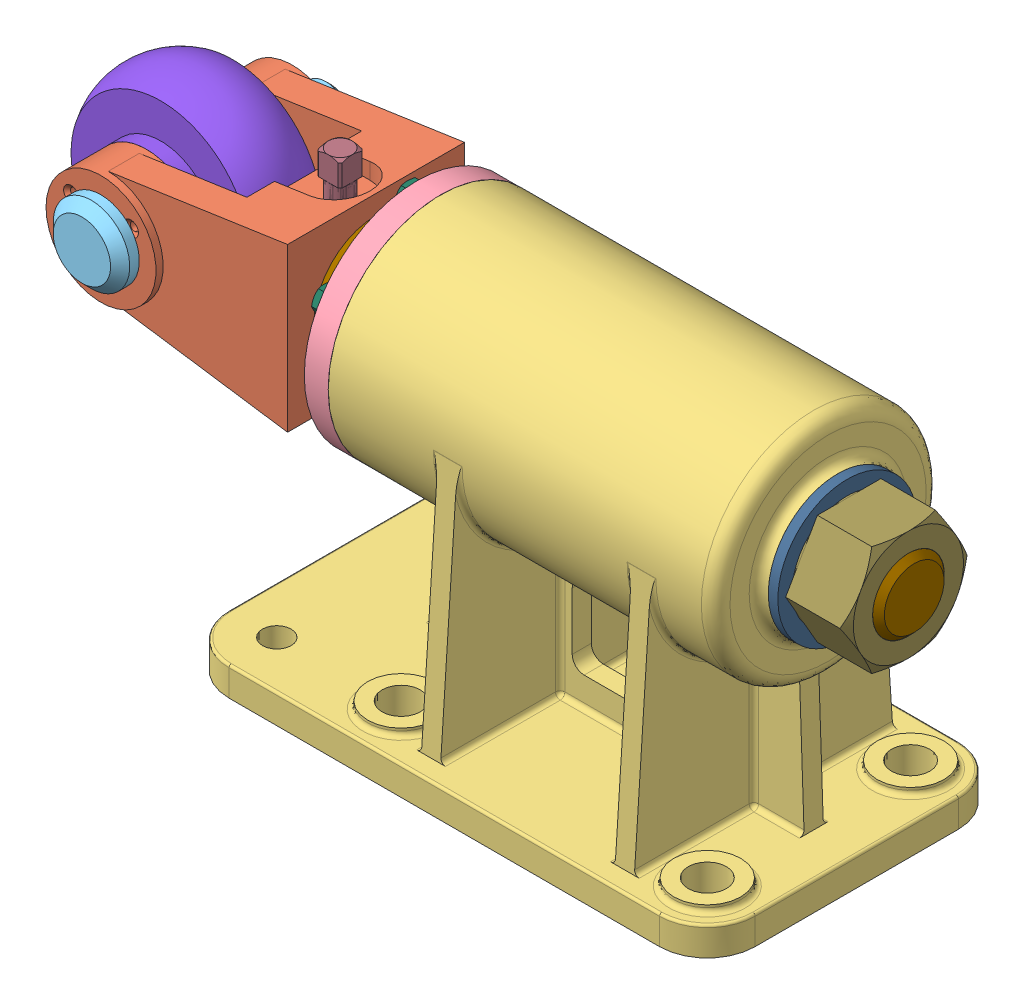
SolidWorks assembly Сборка, configuration Default. Lengths in mm.
Overall size (343.16 167.36 125).
22 component instances, 16 part files, 54 mates.
Components (placement in the parent):
- Втулка-1: Втулка [Default] at (796.4471 -433.9108 62.5) x (-1 0 0) z (0 -0.999974 0.007231) size (35 68 68)
- Вилка-1: Вилка [Default] at (641.6216 -433.9108 32) x (0 1 0) z (1 0 0) size (68 80 98)
- Корпус-1: Корпус [Default] at (807.6216 -550.9108 62.5) size (220 164 125)
- Крышка-1: Крышка [Default] at (727.6216 -433.9108 62.5) size (46 94 94)
- Ось-1: Ось [Default] at (641.6216 -423.9108 102.5) x (0 0 -1) z (0 1 0) size (104 32 32)
- Планка-1: Планка [Default] at (641.6216 -423.9108 19.5) x (1 0 0) z (0 -1 0) size (34 3 8)
- Пружина-1: Пружина [Default] at (888.6216 -433.9108 62.5) x (-1 0 0) z (0 -0.527884 -0.849317) size (97.96 73.13 73.13)
- Ролик-1: Ролик [Default] at (641.6216 -433.9108 62.5) x (0 0 -1) z (-0.999609 -0.027945 0) size (42 84 84)
- Стержень-1: Стержень [Default] at (686.6216 -433.9108 62.5) x (1 0 0) z (0 1 0) size (255 52 52)
- Шайба-1: Шайба [Default] at (913.6216 -433.9108 62.5) x (1 0 0) z (0 0.218534 -0.975829) size (4 58 58)
- parallel_din-1: parallel_din [Parallel key A12 x 8 x 32 DIN 6885] at (739.6216 -450.1144 62.5) x (-1 0 0) z (0 0 1) size (32 8 12)
- hex nut style 1 gradeab_iso-3: hex nut style 1 gradeab_iso [ISO - 4032 - M30 - W - N] at (939.2216 -433.9108 62.5) x (0 0.5 -0.866025) z (1 0 0) size (46 53.12 25.6)
- square head bolt dog pt_din-3: square head bolt dog pt_din [DIN 479 - M10 x 16-C] at (701.6216 -390.9108 62.5) x (0 -1 0) z (-0.707107 0 0.707107) size (26 13 13)
- slotted set screw flat point_iso-3: slotted set screw flat point_iso [ISO 4766 - M6 x 12-N] at (641.915 -444.4067 41.5) x (0 0 1) z (0 1 0) size (12 6 6)
- hex bolt gradeab_iso-4: hex bolt gradeab_iso [ISO 4014 - M6 x 30 x 18-N] at (729.6216 -393.9108 62.5) x (1 0 0) z (0 0.5 0.866025) size (34 11.55 10)
- hex bolt gradeab_iso-6: hex bolt gradeab_iso [ISO 4014 - M6 x 30 x 18-N] at (729.6216 -413.9108 27.859) x (1 0 0) z (0 1 0) size (34 11.55 10)
- hex bolt gradeab_iso-7: hex bolt gradeab_iso [ISO 4014 - M6 x 30 x 18-N] at (729.6216 -453.9108 27.859) x (1 0 0) z (0 0.5 -0.866025) size (34 11.55 10)
- hex bolt gradeab_iso-8: hex bolt gradeab_iso [ISO 4014 - M6 x 30 x 18-N] at (729.6216 -473.9108 62.5) x (1 0 0) z (0 -0.5 -0.866025) size (34 11.55 10)
- hex bolt gradeab_iso-9: hex bolt gradeab_iso [ISO 4014 - M6 x 30 x 18-N] at (729.6216 -453.9108 97.141) x (1 0 0) z (0 -1 0) size (34 11.55 10)
- hex bolt gradeab_iso-10: hex bolt gradeab_iso [ISO 4014 - M6 x 30 x 18-N] at (729.6216 -413.9108 97.141) x (1 0 0) z (0 -0.5 0.866025) size (34 11.55 10)
- pan head cross recess screw_iso-1: pan head cross recess screw_iso [ISO 7045 - M4 x 16 - Z - 16N] at (654.1216 -423.9108 16.4) x (0 0 1) z (-0.923728 -0.383049 0) size (19.02 8 8)
- pan head cross recess screw_iso-3: pan head cross recess screw_iso [ISO 7045 - M4 x 16 - Z - 16N] at (629.1216 -423.9108 16.4) x (0 0 1) z (-0.923728 0.383049 0) size (19.02 8 8)
Mates (geometry in assembly coordinates):
- Parallel2: parallel aligned: plane of Корпус-1 through (897.6216 -538.9108 20) normal (0 1 0); plane of Крышка-1 through (773.6216 -458.1144 56.5) normal (0 1 0)
- Concentric5: concentric aligned: circle of Крышка-1; circle of Стержень-1
- Parallel4: parallel anti-aligned: plane of Крышка-1 through (773.6216 -458.1144 56.5) normal (0 1 0); plane of Стержень-1 through (759.6216 -449.9108 62.5) normal (0 -1 0)
- Coincident11: coincident anti-aligned: plane of Втулка-1 through (798.6216 -457.9102 62.6735) normal (1 0 0); plane of Пружина-1 through (798.6216 -433.9108 62.5) normal (-1 0 0)
- Coincident12: coincident anti-aligned: plane of Втулка-1 through (791.6216 -467.9099 62.7458) normal (-1 0 0); plane of Стержень-1 through (791.6216 -413.9108 62.5) normal (1 0 0)
- Concentric7: concentric anti-aligned: cylinder of Стержень-1 through (598.8447 -433.9108 62.5) axis (-1 0 0) radius 15; cylinder of hex nut style 1 gradeab_iso-3 through (913.6216 -433.9108 62.5) axis (1 0 0) radius 13.25
- Coincident13: coincident anti-aligned: plane of Шайба-1 through (913.6216 -429.9772 44.9351) normal (1 0 0); plane of hex nut style 1 gradeab_iso-3 through (913.6216 -410.9108 75.7791) normal (-1 0 0)
- Parallel5: parallel aligned: plane of Корпус-1 through (897.6216 -538.9108 20) normal (0 1 0); plane of hex nut style 1 gradeab_iso-3 through (913.6216 -410.9108 49.2209) normal (0 1 0)
- Concentric8: concentric anti-aligned: cylinder of Вилка-1 through (618.6216 -433.9108 62.5) axis (1 0 0) radius 20; cylinder of Стержень-1 through (598.8447 -433.9108 62.5) axis (-1 0 0) radius 20
- Coincident15: coincident anti-aligned: plane of Вилка-1 through (716.6216 -433.9108 38.5) normal (1 0 0); plane of Стержень-1 through (716.6216 -413.9108 62.5) normal (-1 0 0)
- Coincident16: coincident anti-aligned: line of Втулка-1 through (791.6216 -433.9108 62.5) axis (1 0 0); line of Пружина-1 through (888.6216 -433.9108 62.5) axis (-1 0 0)
- Lock3: lock: unknown of Втулка-1; unknown of Стержень-1
- Parallel6: parallel: line of Вилка-1 through (716.6216 -467.9108 99.5) axis (0 0 -1); plane of Корпус-1 through (897.6216 -538.9108 20) normal (0 1 0)
- Coincident17: coincident aligned: circle of Вилка-1; cylinder of Ось-1 through (641.6216 -433.9108 34.6227) axis (0 0 -1) radius 10
- Concentric9: concentric anti-aligned: cylinder of Вилка-1 through (629.1216 -423.9108 22.5) axis (0 0 -1) radius 1.7; circle of Планка-1
- Concentric11: concentric anti-aligned: circle of Вилка-1; circle of Планка-1
- Parallel9: parallel anti-aligned: plane of Ось-1 through (409.8471 -427.9108 22.5) normal (0 1 0); plane of Планка-1 through (624.6216 -427.9108 22.5) normal (0 -1 0)
- Coincident22: coincident anti-aligned: plane of Ось-1 through (409.8471 -427.9108 19.5) normal (0 0 1); plane of Планка-1 through (641.6216 -423.9108 19.5) normal (0 0 -1)
- Coincident23: coincident anti-aligned: plane of Вилка-1 through (641.6216 -433.9108 22.5) normal (0 0 -1); plane of Планка-1 through (641.6216 -423.9108 22.5) normal (0 0 1)
- Coincident27: coincident anti-aligned: plane of Стержень-1 through (759.6216 -449.9108 56.5) normal (0 0 1); plane of parallel_din-1 through (759.6216 -458.1144 56.5) normal (0 0 -1)
- Concentric16: concentric anti-aligned: cylinder of Стержень-1 through (739.6216 -449.9108 62.5) axis (0 -1 0) radius 6; cylinder of parallel_din-1 through (739.6216 -458.1144 62.5) axis (0 1 0) radius 6
- Coincident41: coincident anti-aligned: line of Пружина-1 through (888.6216 -433.9108 62.5) axis (-1 0 0); axis of hex nut style 1 gradeab_iso-3 through (914.8724 -433.9108 62.5) axis (1 0 0)
- Coincident42: coincident anti-aligned: line of Корпус-1 through (1195.0065 -433.9108 62.5) axis (-1 0 0); line of hex nut style 1 gradeab_iso-3 through (914.8724 -433.9108 62.5) axis (1 0 0)
- Coincident43: coincident aligned: circle of Корпус-1; circle of Шайба-1
- Coincident44: coincident anti-aligned: plane of Корпус-1 through (888.6216 -466.9108 62.5) normal (-1 0 0); plane of Пружина-1 through (888.6216 -433.9108 62.5) normal (1 0 0)
- Coincident45: coincident anti-aligned: plane of Корпус-1 through (743.6216 -480.9108 62.5) normal (-1 0 0); plane of Крышка-1 through (743.6216 -433.9108 29.5) normal (1 0 0)
- Coincident46: coincident aligned: circle of Корпус-1; circle of Крышка-1
- Parallel16: parallel aligned: plane of Корпус-1 through (897.6216 -538.9108 20) normal (0 1 0); plane of hex nut style 1 gradeab_iso-3 through (913.6216 -410.9108 49.2209) normal (0 1 0)
- Parallel17: parallel anti-aligned: plane of parallel_din-1 through (759.6216 -458.1144 62.5) normal (0 -1 0); plane of Корпус-1 through (897.6216 -538.9108 20) normal (0 1 0)
- Lock7: lock: unknown of Пружина-1; unknown of Стержень-1
- Lock8: lock: unknown of Шайба-1; unknown of hex nut style 1 gradeab_iso-3
- Coincident50: coincident anti-aligned: plane of Крышка-1 through (773.6216 -458.1144 56.5) normal (0 1 0); plane of parallel_din-1 through (759.6216 -458.1144 62.5) normal (0 -1 0)
- Concentric18: concentric aligned: cylinder of Вилка-1 through (701.6216 -467.9118 62.5) axis (0 1 0) radius 5; cylinder of square head bolt dog pt_din-3 through (701.6216 -390.9108 62.5) axis (0 1 0) radius 5
- Parallel19: parallel aligned: plane of Вилка-1 through (686.6216 -463.5108 62.5) normal (-1 0 0); plane of square head bolt dog pt_din-3 through (696.6216 -400.9108 58.3467) normal (-1 0 0)
- Parallel20: parallel anti-aligned: plane of Вилка-1 through (701.6216 -408.9108 62.5) normal (0 1 0); plane of square head bolt dog pt_din-3 through (701.6216 -400.9108 62.5) normal (0 -1 0)
- Concentric19: concentric aligned: line of Корпус-1 through (1195.0065 -433.9108 62.5) axis (-1 0 0); cylinder of slotted set screw flat point_iso-2 through (1050.1594 -433.7358 242.2554) axis (-0.999907 -0.000033 -0.013618) radius 3
- Concentric20: concentric aligned: cylinder of Ролик-1 through (641.915 -444.4067 41.5) axis (0 0 -1) radius 3.3; cylinder of slotted set screw flat point_iso-3 through (641.915 -444.4067 28.8) axis (0 0 -1) radius 3
- Coincident55: coincident: point of Стержень-1; plane of square head bolt dog pt_din-3 through (701.6216 -416.9108 62.5) normal (0 -1 0)
- Parallel21: parallel: plane of Вилка-1 through (686.6216 -463.5108 62.5) normal (-1 0 0); line of slotted set screw flat point_iso-3 through (641.415 -442.0129 41.5) axis (0 -1 0)
- Concentric21: concentric aligned: cylinder of Крышка-1 through (773.6216 -393.9108 62.5) axis (-1 0 0) radius 3.3; cylinder of hex bolt gradeab_iso-4 through (729.6216 -393.9108 62.5) axis (-1 0 0) radius 3
- Coincident57: coincident anti-aligned: plane of Крышка-1 through (733.6216 -433.9108 15.5) normal (-1 0 0); plane of hex bolt gradeab_iso-4 through (733.6216 -388.9108 59.6132) normal (1 0 0)
- Parallel22: parallel aligned: plane of Корпус-1 through (897.6216 -538.9108 20) normal (0 1 0); plane of hex bolt gradeab_iso-4 through (733.6216 -388.9108 59.6132) normal (0 1 0)
- Concentric22: concentric aligned: cylinder of Планка-1 through (654.1216 -423.9108 22.5) axis (0 0 -1) radius 2; cylinder of hex bolt gradeab_iso-12 through (654.1216 -423.9108 16.7) axis (0 0 -1) radius 2
- Coincident59: coincident anti-aligned: plane of Планка-1 through (641.6216 -423.9108 19.5) normal (0 0 -1); circle of hex bolt gradeab_iso-12
- Parallel23: parallel aligned: plane of Вилка-1 through (638.3193 -411.3952 38.5) normal (-0.145114 0.989415 0); plane of hex bolt gradeab_iso-12 through (651.6144 -420.7411 19.5) normal (-0.145114 0.989415 0)
- Coincident60: coincident anti-aligned: plane of Ролик-1 through (641.915 -444.4067 53.5) normal (0 0 -1); plane of slotted set screw flat point_iso-3 through (641.915 -444.4067 53.5) normal (0 0 1)
- Concentric23: concentric anti-aligned: cylinder of Ось-1 through (641.6216 -433.9108 34.6227) axis (0 0 -1) radius 10; cylinder of Ролик-1 through (641.6216 -433.9108 130.7479) axis (0 0 1) radius 10.5
- Coincident61: coincident anti-aligned: plane of Вилка-1 through (641.6216 -433.9108 83.5) normal (0 0 -1); plane of Ролик-1 through (652.1175 -433.6174 83.5) normal (0 0 1)
- Coincident63: coincident anti-aligned: plane of Корпус-1 through (717.6216 -538.9108 0) normal (0 0 -1)
- Parallel27: parallel aligned: plane of Корпус-1 through (897.6216 -538.9108 20) normal (0 1 0)
- Lock9: lock: unknown of Вилка-1; unknown of Ролик-1
- Concentric24: concentric aligned: cylinder of Вилка-1 through (654.1216 -423.9108 22.5) axis (0 0 -1) radius 1.7; cylinder of pan head cross recess screw_iso-1 through (654.1216 -423.9108 -9) axis (0 0 -1) radius 2
- Coincident65: coincident anti-aligned: plane of Планка-1 through (641.6216 -423.9108 19.5) normal (0 0 -1); plane of pan head cross recess screw_iso-1 through (653.3555 -422.0634 19.5) normal (0 0 1)
- Lock11: lock: unknown of Планка-1; unknown of pan head cross recess screw_iso-1
